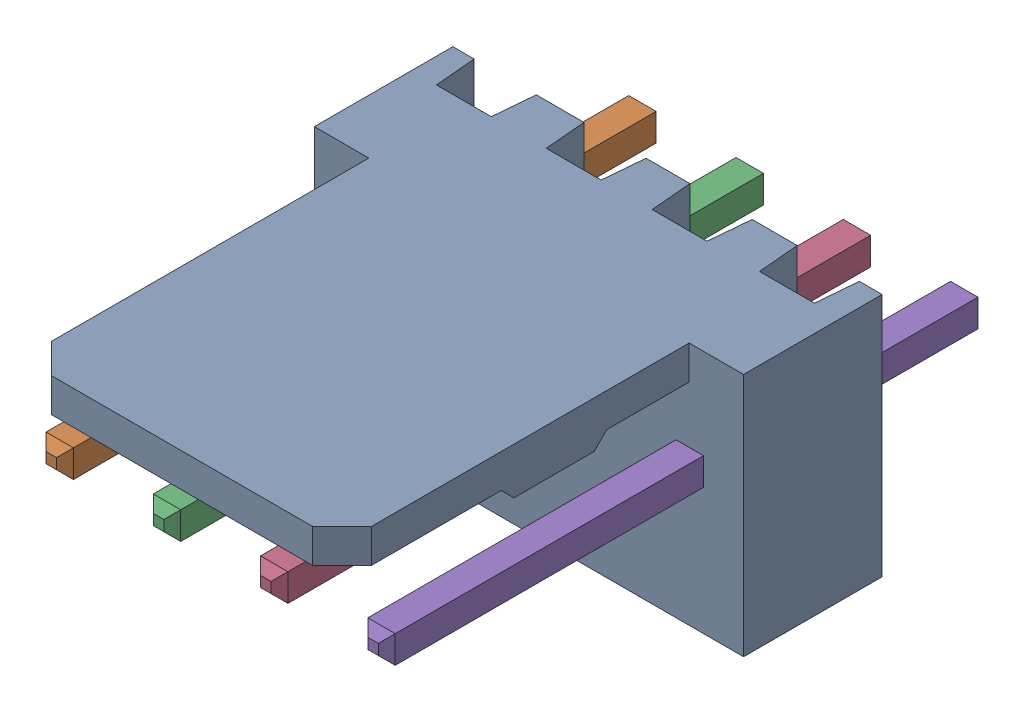
SolidWorks assembly Molex PCB 4 pin v3_1, configuration Default. Lengths in mm.
Overall size (10.16 5.79 14.92).
5 component instances, 2 part files, 0 mates.
Components (placement in the parent):
- BASE9710016-1: BASE9710016 [Default] at (2.54 2.895 -8.22) size (10.16 5.79 11.5)
- PINO9710016-1: PINO9710016 [Default] at (1.27 3.325 -0.72) size (0.65 0.65 14.2)
- PINO9710016-2: PINO9710016 [Default] at (3.81 3.325 -0.72) size (0.65 0.65 14.2)
- PINO9710016-3: PINO9710016 [Default] at (6.35 3.325 -0.72) size (0.65 0.65 14.2)
- PINO9710016-4: PINO9710016 [Default] at (8.89 3.325 -0.72) size (0.65 0.65 14.2)
